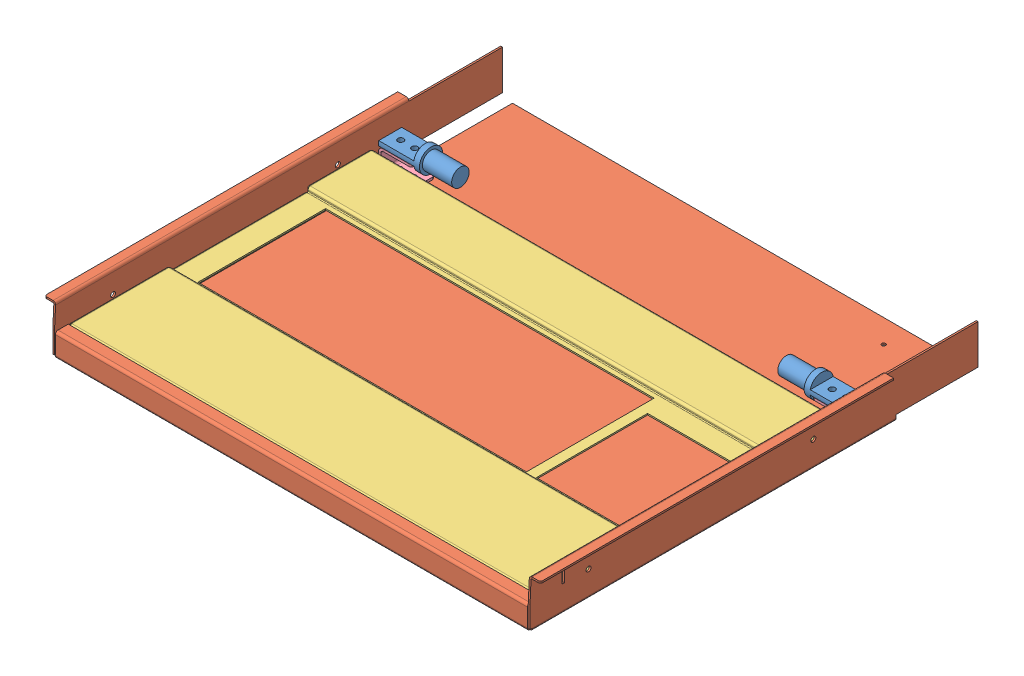
SolidWorks assembly BASE, configuration Valor predeterminado. Lengths in mm.
Overall size (423.46 41 382.6).
20 component instances, 5 part files, 43 mates.
Components (placement in the parent):
- 500080100-1: 500080100 [Default<Como usinado>] at (371.56 22 -283.6) x (0 0 1) z (1 0 0) size (20 20 60)
- 500060100-1: 500060100 [Valor predeterminado] at origin size (423.46 41 382.6)
- 500050100-1: 500050100 [Valor predeterminado] at (202.275 18.5 -54.3) size (404.56 18.5 259.6)
- 500090100-1: 500090100 [Default] at (5.035 2 -283.6) x (-1 0 0) z (0 0 1) size (28 20 20)
- 500090100-2: 500090100 [Default] at (399.56 2 -283.6) x (1 0 0) z (0 0 -1) size (28 20 20)
- 500080100-2: 500080100 [Default<Como usinado>] at (33.035 22 -283.6) x (0 0 -1) z (-1 0 0) size (20 20 60)
- PARAFUSO ALLEN CÔNICO DIN 7991-1: PARAFUSO ALLEN CÔNICO DIN 7991 [M3x05] at (392.56 3.5 -283.6) x (0 -1 0) z (0.853313 0 -0.521399) size (5 6 6)
- PARAFUSO ALLEN CÔNICO DIN 7991-2: PARAFUSO ALLEN CÔNICO DIN 7991 [M3x05] at (380.56 3.5 -283.6) x (0 -1 0) z (-0.853313 0 0.521399) size (5 6 6)
- PARAFUSO ALLEN CÔNICO DIN 7991-3: PARAFUSO ALLEN CÔNICO DIN 7991 [M3x05] at (399.3618 3.5 -241.3933) x (0 -1 0) z (-0.853313 0 0.521399) size (5 6 6)
- PARAFUSO ALLEN CÔNICO DIN 7991-4: PARAFUSO ALLEN CÔNICO DIN 7991 [M3x05] at (399.3618 3.5 -157.0683) x (0 -1 0) z (0.853313 0 -0.521399) size (5 6 6)
- PARAFUSO ALLEN CÔNICO DIN 7991-5: PARAFUSO ALLEN CÔNICO DIN 7991 [M3x05] at (399.3618 3.5 -55.2683) x (0 -1 0) z (0.853313 0 -0.521399) size (5 6 6)
- PARAFUSO ALLEN CÔNICO DIN 7991-6: PARAFUSO ALLEN CÔNICO DIN 7991 [M3x05] at (372.275 3.5 -17.5724) x (0 -1 0) z (0.853313 0 -0.521399) size (5 6 6)
- PARAFUSO ALLEN CÔNICO DIN 7991-7: PARAFUSO ALLEN CÔNICO DIN 7991 [M3x05] at (272.275 3.5 -17.5724) x (0 -1 0) z (0.853313 0 -0.521399) size (5 6 6)
- PARAFUSO ALLEN CÔNICO DIN 7991-8: PARAFUSO ALLEN CÔNICO DIN 7991 [M3x05] at (132.275 3.5 -17.5724) x (0 -1 0) z (0.853313 0 -0.521399) size (5 6 6)
- PARAFUSO ALLEN CÔNICO DIN 7991-10: PARAFUSO ALLEN CÔNICO DIN 7991 [M3x05] at (32.275 3.5 -17.5724) x (0 -1 0) z (0.853313 0 -0.521399) size (5 6 6)
- PARAFUSO ALLEN CÔNICO DIN 7991-11: PARAFUSO ALLEN CÔNICO DIN 7991 [M3x05] at (5.1933 3.5 -55.2683) x (0 -1 0) z (0.853313 0 -0.521399) size (5 6 6)
- PARAFUSO ALLEN CÔNICO DIN 7991-12: PARAFUSO ALLEN CÔNICO DIN 7991 [M3x05] at (5.1933 3.5 -157.0683) x (0 -1 0) z (0.853313 0 -0.521399) size (5 6 6)
- PARAFUSO ALLEN CÔNICO DIN 7991-13: PARAFUSO ALLEN CÔNICO DIN 7991 [M3x05] at (5.1933 3.5 -241.3933) x (0 -1 0) z (0.853313 0 -0.521399) size (5 6 6)
- PARAFUSO ALLEN CÔNICO DIN 7991-14: PARAFUSO ALLEN CÔNICO DIN 7991 [M3x05] at (12.035 3.5 -283.6) x (0 -1 0) z (0.853313 0 -0.521399) size (5 6 6)
- PARAFUSO ALLEN CÔNICO DIN 7991-15: PARAFUSO ALLEN CÔNICO DIN 7991 [M3x05] at (24.035 3.5 -283.6) x (0 -1 0) z (0.853313 0 -0.521399) size (5 6 6)
Mates (geometry in assembly coordinates):
- Coincidente87: coincident anti-aligned: plane of 500090100-2 through (399.56 20 -283.6) normal (0 1 0); plane of 500080100-1 through (371.56 20 -293.6) normal (0 -1 0)
- Coincidente12: coincident anti-aligned: plane of 500060100-1 through (0 0 0) normal (0 1 0); plane of 500050100-1 through (202.275 0 -54.3) normal (0 -1 0)
- Concêntrico7: concentric anti-aligned: cone of 500060100-1 through (32.275 -1.5 -17.5724) axis (0 1 0); cylinder of 500050100-1 through (32.275 0 -17.5724) axis (0 -1 0) radius 1.65
- Paralelo7: parallel aligned: plane of 500060100-1 through (0 0 0) normal (0 0 1); plane of 500050100-1 through (202.275 18.5 -11) normal (0 0 1)
- Paralelo10: parallel aligned: plane of 500060100-1 through (0 -1.5 -382.6) normal (0 0 -1); plane of 500090100-1 through (5.035 64.482 -293.6) normal (0 0 -1)
- Coincidente35: coincident anti-aligned: plane of 500060100-1 through (0 0 0) normal (0 1 0); plane of 500090100-2 through (373.56 0 -293.6) normal (0 -1 0)
- Distância6: distance = 3 mm anti-aligned: plane of 500090100-2 through (401.56 0 -293.6) normal (1 0 0); plane of 500060100-1 through (404.56 0 0) normal (-1 0 0)
- Distância7: distance = 89 mm aligned: plane of 500090100-1 through (56.26 20 -293.6) normal (0 0 -1); plane of 500060100-1 through (-1.5 0 -382.6) normal (0 0 -1)
- Coincidente43: coincident anti-aligned: plane of 500060100-1 through (0 0 0) normal (0 1 0); plane of 500090100-1 through (31.035 0 -273.6) normal (0 -1 0)
- Coincidente36: coincident aligned: plane of 500090100-1 through (5.035 64.482 -273.6) normal (0 0 1); plane of 500090100-2 through (399.56 64.482 -273.6) normal (0 0 1)
- Concêntrico24: concentric anti-aligned: cylinder of 500090100-1 through (12.035 20 -283.6) axis (0 1 0) radius 2.5; cylinder of 500080100-2 through (12.035 20 -283.6) axis (0 -1 0) radius 2.5
- Coincidente84: coincident anti-aligned: plane of 500090100-1 through (5.035 20 -283.6) normal (0 1 0); plane of 500080100-2 through (33.035 20 -273.6) normal (0 -1 0)
- Concêntrico25: concentric anti-aligned: cylinder of 500080100-1 through (392.56 20 -283.6) axis (0 -1 0) radius 2.5; cylinder of 500090100-2 through (392.56 20 -283.6) axis (0 1 0) radius 2.5
- Concêntrico26: concentric anti-aligned: cylinder of 500080100-1 through (380.56 20 -283.6) axis (0 -1 0) radius 2.5; cylinder of 500090100-2 through (380.56 20 -283.6) axis (0 1 0) radius 2.5
- Concêntrico27: concentric anti-aligned: cylinder of 500090100-1 through (24.035 20 -283.6) axis (0 1 0) radius 2.5; cylinder of 500080100-2 through (24.035 20 -283.6) axis (0 -1 0) radius 2.5
- Concêntrico28: concentric aligned: cone of 500060100-1 through (392.56 -1.5 -283.6) axis (0 1 0); cylinder of PARAFUSO ALLEN CÔNICO DIN 7991-1 through (392.56 13.6033 -283.6) axis (0 1 0) radius 1.25
- Coincidente88: coincident aligned: plane of 500060100-1 through (0 -1.5 0) normal (0 -1 0); plane of PARAFUSO ALLEN CÔNICO DIN 7991-1 through (390.9958 -1.5 -286.1599) normal (0 -1 0)
- Concêntrico29: concentric anti-aligned: cylinder of 500090100-2 through (380.56 0 -283.6) axis (0 -1 0) radius 1.65; cylinder of PARAFUSO ALLEN CÔNICO DIN 7991-2 through (380.56 13.6033 -283.6) axis (0 1 0) radius 1.25
- Coincidente89: coincident aligned: plane of 500060100-1 through (0 -1.5 0) normal (0 -1 0); plane of PARAFUSO ALLEN CÔNICO DIN 7991-2 through (382.1242 -1.5 -281.0401) normal (0 -1 0)
- Concêntrico30: concentric anti-aligned: cylinder of 500050100-1 through (399.3618 0 -241.3933) axis (0 -1 0) radius 1.65; cylinder of PARAFUSO ALLEN CÔNICO DIN 7991-3 through (399.3618 13.6033 -241.3933) axis (0 1 0) radius 1.25
- Coincidente90: coincident aligned: plane of 500060100-1 through (0 -1.5 0) normal (0 -1 0); plane of PARAFUSO ALLEN CÔNICO DIN 7991-3 through (400.926 -1.5 -238.8334) normal (0 -1 0)
- Concêntrico31: concentric aligned: cone of 500060100-1 through (399.3618 -1.5 -157.0683) axis (0 1 0); cylinder of PARAFUSO ALLEN CÔNICO DIN 7991-4 through (399.3618 13.6033 -157.0683) axis (0 1 0) radius 1.25
- Coincidente91: coincident aligned: plane of 500060100-1 through (0 -1.5 0) normal (0 -1 0); plane of PARAFUSO ALLEN CÔNICO DIN 7991-4 through (397.7976 -1.5 -159.6282) normal (0 -1 0)
- Concêntrico32: concentric aligned: cone of 500060100-1 through (399.3618 -1.5 -55.2683) axis (0 1 0); cylinder of PARAFUSO ALLEN CÔNICO DIN 7991-5 through (399.3618 13.6033 -55.2683) axis (0 1 0) radius 1.25
- Coincidente92: coincident aligned: plane of 500060100-1 through (0 -1.5 0) normal (0 -1 0); plane of PARAFUSO ALLEN CÔNICO DIN 7991-5 through (397.7976 -1.5 -57.8282) normal (0 -1 0)
- Concêntrico33: concentric aligned: cone of 500060100-1 through (372.275 -1.5 -17.5724) axis (0 1 0); cylinder of PARAFUSO ALLEN CÔNICO DIN 7991-6 through (372.275 13.6033 -17.5724) axis (0 1 0) radius 1.25
- Coincidente93: coincident aligned: plane of 500060100-1 through (0 -1.5 0) normal (0 -1 0); plane of PARAFUSO ALLEN CÔNICO DIN 7991-6 through (370.7108 -1.5 -20.1324) normal (0 -1 0)
- Concêntrico34: concentric aligned: cone of 500060100-1 through (272.275 -1.5 -17.5724) axis (0 1 0); cylinder of PARAFUSO ALLEN CÔNICO DIN 7991-7 through (272.275 13.6033 -17.5724) axis (0 1 0) radius 1.25
- Coincidente94: coincident aligned: plane of 500060100-1 through (0 -1.5 0) normal (0 -1 0); plane of PARAFUSO ALLEN CÔNICO DIN 7991-7 through (270.7108 -1.5 -20.1324) normal (0 -1 0)
- Concêntrico35: concentric aligned: cone of 500060100-1 through (132.275 -1.5 -17.5724) axis (0 1 0); cylinder of PARAFUSO ALLEN CÔNICO DIN 7991-8 through (132.275 13.6033 -17.5724) axis (0 1 0) radius 1.25
- Coincidente95: coincident aligned: plane of 500060100-1 through (0 -1.5 0) normal (0 -1 0); plane of PARAFUSO ALLEN CÔNICO DIN 7991-8 through (130.7108 -1.5 -20.1324) normal (0 -1 0)
- Concêntrico36: concentric aligned: cone of 500060100-1 through (32.275 -1.5 -17.5724) axis (0 1 0); cylinder of PARAFUSO ALLEN CÔNICO DIN 7991-10 through (32.275 13.6033 -17.5724) axis (0 1 0) radius 1.25
- Coincidente96: coincident aligned: plane of 500060100-1 through (0 -1.5 0) normal (0 -1 0); plane of PARAFUSO ALLEN CÔNICO DIN 7991-10 through (30.7108 -1.5 -20.1324) normal (0 -1 0)
- Concêntrico37: concentric aligned: cone of 500060100-1 through (5.1933 -1.5 -55.2683) axis (0 1 0); cylinder of PARAFUSO ALLEN CÔNICO DIN 7991-11 through (5.1933 13.6033 -55.2683) axis (0 1 0) radius 1.25
- Coincidente97: coincident aligned: plane of 500060100-1 through (0 -1.5 0) normal (0 -1 0); plane of PARAFUSO ALLEN CÔNICO DIN 7991-11 through (3.6291 -1.5 -57.8282) normal (0 -1 0)
- Concêntrico38: concentric aligned: cone of 500060100-1 through (5.1933 -1.5 -157.0683) axis (0 1 0); cylinder of PARAFUSO ALLEN CÔNICO DIN 7991-12 through (5.1933 13.6033 -157.0683) axis (0 1 0) radius 1.25
- Coincidente98: coincident aligned: plane of 500060100-1 through (0 -1.5 0) normal (0 -1 0); plane of PARAFUSO ALLEN CÔNICO DIN 7991-12 through (3.6291 -1.5 -159.6282) normal (0 -1 0)
- Concêntrico39: concentric aligned: cone of 500060100-1 through (5.1933 -1.5 -241.3933) axis (0 1 0); cylinder of PARAFUSO ALLEN CÔNICO DIN 7991-13 through (5.1933 13.6033 -241.3933) axis (0 1 0) radius 1.25
- Coincidente99: coincident aligned: plane of 500060100-1 through (0 -1.5 0) normal (0 -1 0); plane of PARAFUSO ALLEN CÔNICO DIN 7991-13 through (3.6291 -1.5 -243.9532) normal (0 -1 0)
- Concêntrico40: concentric aligned: cone of 500060100-1 through (12.035 -1.5 -283.6) axis (0 1 0); cylinder of PARAFUSO ALLEN CÔNICO DIN 7991-14 through (12.035 13.6033 -283.6) axis (0 1 0) radius 1.25
- Coincidente100: coincident aligned: plane of 500060100-1 through (0 -1.5 0) normal (0 -1 0); plane of PARAFUSO ALLEN CÔNICO DIN 7991-14 through (10.4708 -1.5 -286.1599) normal (0 -1 0)
- Concêntrico41: concentric aligned: cone of 500060100-1 through (24.035 -1.5 -283.6) axis (0 1 0); cylinder of PARAFUSO ALLEN CÔNICO DIN 7991-15 through (24.035 13.6033 -283.6) axis (0 1 0) radius 1.25
- Coincidente101: coincident aligned: plane of 500060100-1 through (0 -1.5 0) normal (0 -1 0); plane of PARAFUSO ALLEN CÔNICO DIN 7991-15 through (22.4708 -1.5 -286.1599) normal (0 -1 0)
